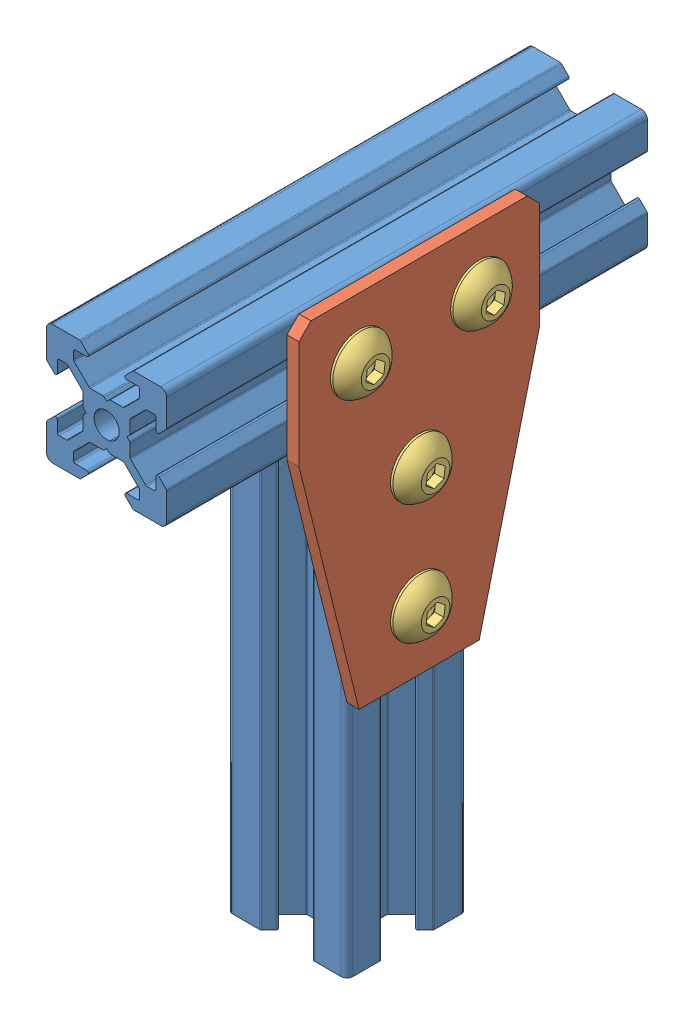
SolidWorks assembly Т-пластина 20 серия 2х3 4отв 40х60х2 усил СБ, configuration По умолчанию. Lengths in mm.
Overall size (24.75 100 80).
7 component instances, 3 part files, 14 mates.
Components (placement in the parent):
- 2020100-1: 2020100 [По умолчанию] at origin size (20 20 80)
- 2020100-2: 2020100 [По умолчанию] at (0 -90 40) x (1 0 0) z (0 1 0) size (20 20 80)
- Т-пластина 20 серия 2х3 4отв 40х60х2 усил.-1: Т-пластина 20 серия 2х3 4отв 40х60х2 усил. [По умолчанию] at (10 -50 40) x (0 0 -1) z (0 -1 0) size (40 2 60)
- socket button head screw_iso-5: socket button head screw_iso [ISO 7380 - M5 x 10 - 10N] at (14.75 0 50) x (-1 0 0) z (0 0.924225 0.381849) size (12.75 9.5 9.5)
- socket button head screw_iso-6: socket button head screw_iso [ISO 7380 - M5 x 10 - 10N] at (14.75 0 30) x (-1 0 0) z (0 0.924225 0.381849) size (12.75 9.5 9.5)
- socket button head screw_iso-7: socket button head screw_iso [ISO 7380 - M5 x 10 - 10N] at (14.75 -20 40) x (-1 0 0) z (0 0.924225 0.381849) size (12.75 9.5 9.5)
- socket button head screw_iso-8: socket button head screw_iso [ISO 7380 - M5 x 10 - 10N] at (14.75 -40 40) x (-1 0 0) z (0 0.924225 0.381849) size (12.75 9.5 9.5)
Mates (geometry in assembly coordinates):
- Совпадение1: coincident aligned: plane of 2020100-1 through (10 -10 80) normal (1 0 0); plane of 2020100-2 through (10 -10 30) normal (1 0 0)
- Совпадение2: coincident anti-aligned: plane of 2020100-1 through (10 -10 80) normal (0 -1 0); plane of 2020100-2 through (0 -10 40) normal (0 1 0)
- Расстояние1: distance = 30 mm aligned: plane of 2020100-2 through (-10 -10 50) normal (0 0 1); plane of 2020100-1 through (0 0 80) normal (0 0 1)
- Совпадение3: coincident anti-aligned: plane of 2020100-1 through (10 -10 80) normal (1 0 0); plane of Т-пластина 20 серия 2х3 4отв 40х60х2 усил.-1 through (10 -50 40) normal (-1 0 0)
- Совпадение4: coincident aligned: plane of 2020100-1 through (10 10 80) normal (0 1 0); plane of Т-пластина 20 серия 2х3 4отв 40х60х2 усил.-1 through (12 10 60) normal (0 1 0)
- Совпадение5: coincident: plane of 2020100-2 through (10 -10 50) normal (0 0 1); line of Т-пластина 20 серия 2х3 4отв 40х60х2 усил.-1 through (12 -50 50) axis (-1 0 0)
- Концентричный1: concentric aligned: cylinder of Т-пластина 20 серия 2х3 4отв 40х60х2 усил.-1 through (12 0 50) axis (1 0 0) radius 2.75; cylinder of socket button head screw_iso-5 through (14.75 0 50) axis (1 0 0) radius 4.75
- Совпадение6: coincident anti-aligned: plane of Т-пластина 20 серия 2х3 4отв 40х60х2 усил.-1 through (12 -50 40) normal (1 0 0); plane of socket button head screw_iso-5 through (12 -0.9546 52.3106) normal (-1 0 0)
- Концентричный2: concentric aligned: cylinder of Т-пластина 20 серия 2х3 4отв 40х60х2 усил.-1 through (12 0 30) axis (1 0 0) radius 2.75; cylinder of socket button head screw_iso-6 through (14.75 0 30) axis (1 0 0) radius 4.75
- Совпадение7: coincident anti-aligned: plane of Т-пластина 20 серия 2х3 4отв 40х60х2 усил.-1 through (12 -50 40) normal (1 0 0); plane of socket button head screw_iso-6 through (12 -0.9546 32.3106) normal (-1 0 0)
- Концентричный3: concentric aligned: cylinder of Т-пластина 20 серия 2х3 4отв 40х60х2 усил.-1 through (12 -20 40) axis (1 0 0) radius 2.75; cylinder of socket button head screw_iso-7 through (14.75 -20 40) axis (1 0 0) radius 4.75
- Совпадение8: coincident anti-aligned: plane of Т-пластина 20 серия 2х3 4отв 40х60х2 усил.-1 through (12 -50 40) normal (1 0 0); plane of socket button head screw_iso-7 through (12 -20.9546 42.3106) normal (-1 0 0)
- Концентричный4: concentric aligned: cylinder of Т-пластина 20 серия 2х3 4отв 40х60х2 усил.-1 through (12 -40 40) axis (1 0 0) radius 2.75; cylinder of socket button head screw_iso-8 through (14.75 -40 40) axis (1 0 0) radius 4.75
- Совпадение9: coincident anti-aligned: plane of Т-пластина 20 серия 2х3 4отв 40х60х2 усил.-1 through (12 -50 40) normal (1 0 0); plane of socket button head screw_iso-8 through (12 -40.9546 42.3106) normal (-1 0 0)
